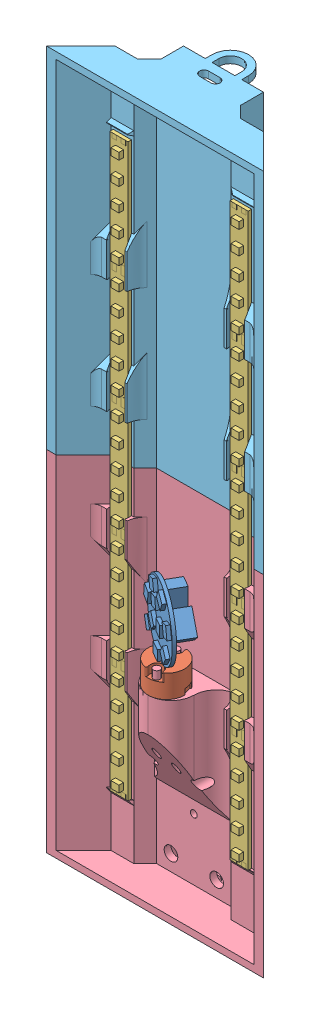
SolidWorks assembly Center-Decke, configuration Standard. Lengths in mm.
Overall size (95 306 46.66).
6 component instances, 5 part files, 15 mates.
Components (placement in the parent):
- G4 LED-1: G4 LED [Standard] at (-69.7688 71.9428 102.8196) x (-0.866025 0 -0.5) z (0 1 0) size (30 9.9 34.79)
- G4 Sockel-1: G4 Sockel [Standard] at (-69.3938 46.9428 102.1701) x (0.258819 0 0.965926) z (0 1 0) size (16 16 33.5)
- LED-Bar-1: LED-Bar [Standard] at (-39.0865 238.9428 95.1701) x (0 1 0) z (1 0 0) size (250 3.5 8)
- LED-Bar-2: LED-Bar [Standard] at (-91.7012 238.9428 95.1701) x (0 1 0) z (1 0 0) size (250 3.5 8)
- Center-Decke-Gehäuse-Left-1: Center-Decke-Gehäuse-Left [Standard] at (-69.3938 -38.0572 77.1701) size (95 157.8 44)
- Center-Decke-Gehäuse-Right-1: Center-Decke-Gehäuse-Right [Standard] at (-69.3938 267.9428 77.1701) x (-1 0 0) z (0 0 1) size (95 153 41)
Mates (geometry in assembly coordinates):
- Deckungsgleich1: coincident anti-aligned: plane of LED-Bar-1 through (-39.0865 238.9428 95.1701) normal (0 0 -1); plane of Center-Decke-Gehäuse-Left-1 through (-48.1365 114.9428 95.1701) normal (0 0 1)
- Deckungsgleich2: coincident anti-aligned: plane of LED-Bar-2 through (-91.7012 238.9428 95.1701) normal (0 0 -1); plane of Center-Decke-Gehäuse-Left-1 through (-90.6512 114.9428 95.1701) normal (0 0 1)
- Deckungsgleich7: coincident anti-aligned: plane of G4 Sockel-1 through (-69.3938 46.9428 102.1701) normal (0 -1 0); plane of Center-Decke-Gehäuse-Left-1 through (-79.3938 46.9428 110.1701) normal (0 1 0)
- Konzentrisch1: concentric anti-aligned: cylinder of G4 Sockel-1 through (-70.9468 46.9428 96.3745) axis (0 1 0) radius 1.5; cylinder of Center-Decke-Gehäuse-Left-1 through (-70.9468 56.9428 96.3745) axis (0 -1 0) radius 1.5
- Konzentrisch2: concentric anti-aligned: cylinder of G4 Sockel-1 through (-67.8409 46.9428 107.9656) axis (0 1 0) radius 1.5; cylinder of Center-Decke-Gehäuse-Left-1 through (-67.8409 56.9428 107.9656) axis (0 -1 0) radius 1.5
- Konzentrisch3: concentric anti-aligned: cylinder of G4 Sockel-1 through (-67.2288 46.9428 103.4201) axis (0 1 0) radius 0.75; cylinder of G4 LED-1 through (-67.2288 59.6577 103.4201) axis (0 -1 0) radius 0.75
- Konzentrisch4: concentric anti-aligned: cylinder of G4 LED-1 through (-71.5589 59.6577 100.9201) axis (0 -1 0) radius 0.75; cylinder of G4 Sockel-1 through (-71.5589 46.9428 100.9201) axis (0 1 0) radius 0.75
- Tangential2: tangent anti-aligned: cylinder of G4 LED-1 through (-70.4688 71.9428 104.032) axis (0.5 0 -0.866025) radius 15; plane of G4 Sockel-1 through (-69.3938 56.9428 102.1701) normal (0 1 0)
- Deckungsgleich8: coincident anti-aligned: plane of Center-Decke-Gehäuse-Left-1 through (-69.3938 114.9428 77.1701) normal (0 1 0); plane of Center-Decke-Gehäuse-Right-1 through (-69.3938 114.9428 77.1701) normal (0 -1 0)
- Deckungsgleich9: coincident anti-aligned: line of Center-Decke-Gehäuse-Left-1 through (-101.8938 114.9428 92.1701) axis (-0.707107 0 0.707107); line of Center-Decke-Gehäuse-Right-1 through (-107.7015 114.9428 97.9777) axis (0.707107 0 -0.707107)
- Deckungsgleich10: coincident anti-aligned: line of Center-Decke-Gehäuse-Left-1 through (-30.9448 114.9428 98.1191) axis (-0.707107 0 -0.707107); line of Center-Decke-Gehäuse-Right-1 through (-36.8938 114.9428 92.1701) axis (0.707107 0 0.707107)
- Deckungsgleich11: coincident anti-aligned: plane of LED-Bar-2 through (-99.7012 238.9428 96.6701) normal (-1 0 0); plane of Center-Decke-Gehäuse-Left-1 through (-99.7012 31.4428 98.1701) normal (1 0 0)
- Deckungsgleich12: coincident anti-aligned: plane of LED-Bar-1 through (-39.0865 238.9428 96.6701) normal (1 0 0); plane of Center-Decke-Gehäuse-Left-1 through (-39.0865 31.4428 98.1701) normal (-1 0 0)
- Deckungsgleich13: coincident anti-aligned: plane of LED-Bar-1 through (-39.0865 -11.0572 96.6701) normal (0 -1 0); plane of Center-Decke-Gehäuse-Left-1 through (-48.1365 -11.0572 96.1701) normal (0 1 0)
- Deckungsgleich14: coincident anti-aligned: plane of LED-Bar-2 through (-91.7012 -11.0572 96.6701) normal (0 -1 0); plane of Center-Decke-Gehäuse-Left-1 through (-90.6512 -11.0572 96.1701) normal (0 1 0)
